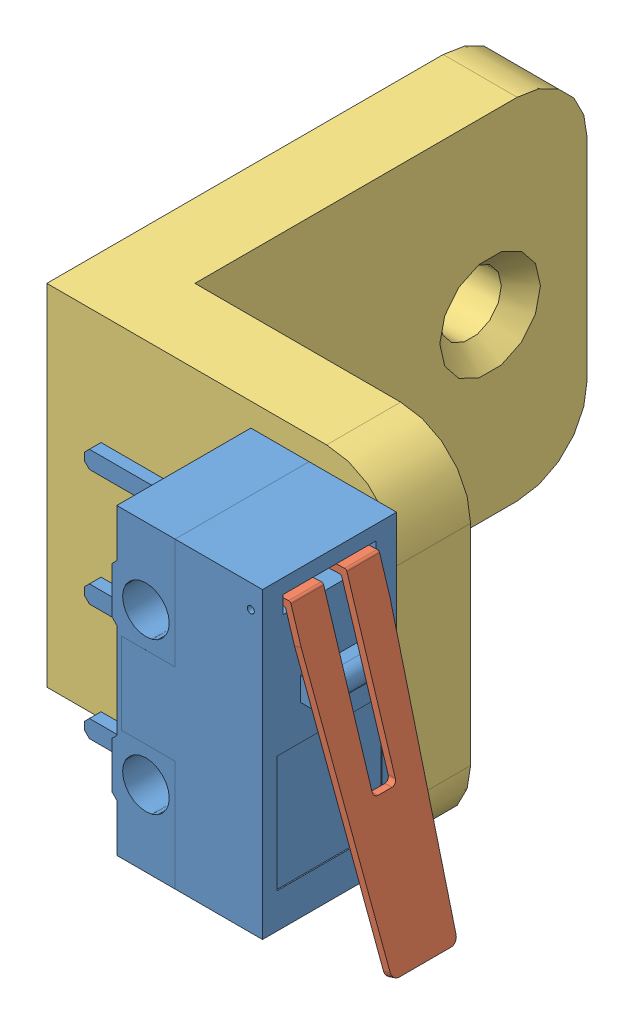
SolidWorks assembly cf_limit_switch_mount_assem, configuration Default. Lengths in mm.
Overall size (19.1 15 25.78).
4 component instances, 3 part files, 3 mates.
Components (placement in the parent):
- Microsassem-1: Microsassem [Default] at (8.1934 39.6678 64.0404) x (0 -1 0) z (1 0 0) size (13.52 5.8 14.35)
  - Micro Switch-1: Micro Switch [Default] at (5.5673 7.1501 9.4199) size (13.05 5.8 11.25)
  - Lever-1: Lever [Default] at (-0.0622 9.0501 14.6641) x (0.999157 0 0.041042) z (0 -1 0) size (12.63 4.59 4)
- cf_limit_switch_mount-1: cf_limit_switch_mount [Default] at (8.8633 34.1005 54.0152) size (15 15 20)
Mates (geometry in assembly coordinates):
- Concentric1: concentric anti-aligned: cylinder of Microsassem-1/Micro Switch-1 through (18.8633 30.8505 60.0153) axis (0 0 -1) radius 1; cylinder of cf_limit_switch_mount-1 through (18.8633 30.8505 54.0152) axis (0 0 1) radius 1.1303
- Concentric2: concentric anti-aligned: cylinder of Microsassem-1/Micro Switch-1 through (18.8633 37.3505 60.0153) axis (0 0 -1) radius 1; cylinder of cf_limit_switch_mount-1 through (18.8633 37.3505 54.0152) axis (0 0 1) radius 1.1303
- Coincident1: coincident anti-aligned: plane of Microsassem-1/Micro Switch-1 through (23.8633 40.6006 54.0152) normal (0 0 -1); plane of cf_limit_switch_mount-1 through (23.8633 41.6005 54.0152) normal (0 0 1)
